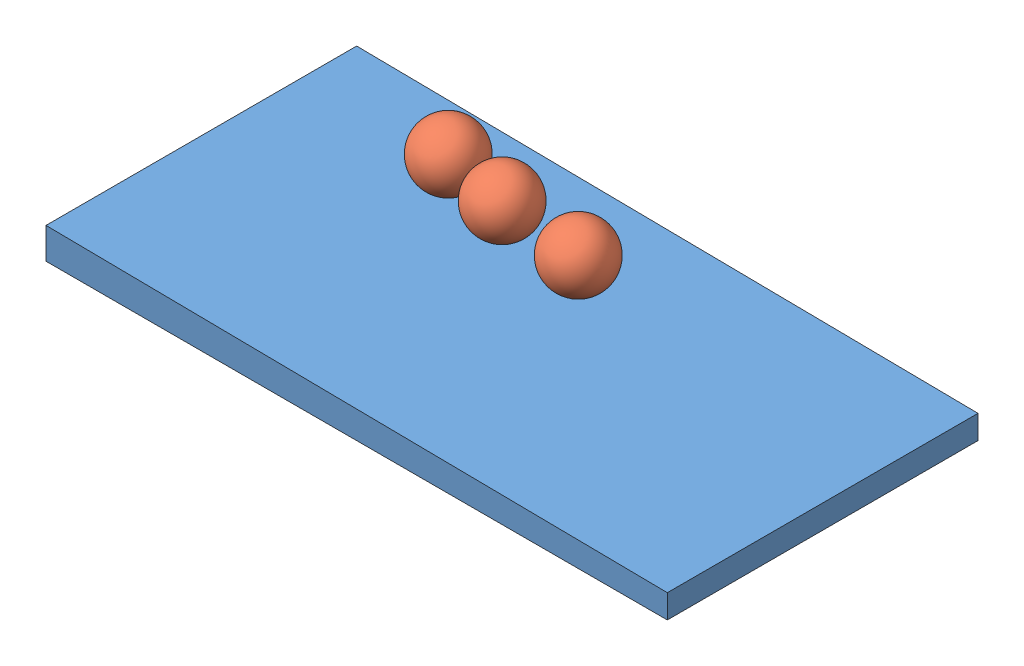
SolidWorks assembly Assem1, configuration ﾃﾞﾌｫﾙﾄ. Lengths in mm.
Overall size (200 34.42 100).
4 component instances, 2 part files, 3 mates.
Components (placement in the parent):
- 板-1: 板 [ﾃﾞﾌｫﾙﾄ] at (-14.4719 5.2827 200) size (200 10 100)
- Copy of 直径２０mmのパチンコ玉^Assem1-1: Copy of 直径２０mmのパチンコ玉^Assem1 [ﾃﾞﾌｫﾙﾄ] at (-11.6871 24.056 181.454) x (-0.958709 0.280638 -0.046044) z (0.07397 0.402403 0.912469) size (20 20 20) (virtual)
- Copy of 直径２０mmのパチンコ玉^Assem1-2: Copy of 直径２０mmのパチンコ玉^Assem1 [ﾃﾞﾌｫﾙﾄ] at (-60.215 24.6355 174.7735) x (-0.53463 -0.715781 0.449252) z (0.558454 0.099751 0.823516) size (20 20 20) (virtual)
- Copy of 直径２０mmのパチンコ玉^Assem1-3: Copy of 直径２０mmのパチンコ玉^Assem1 [ﾃﾞﾌｫﾙﾄ] at (-38.8183 24.38 178.8186) x (-0.863576 -0.070244 -0.499302) z (-0.344174 -0.641556 0.685529) size (20 20 20) (virtual)
Mates (geometry in assembly coordinates):
- 正接1: tangent anti-aligned: plane of 板-1 through (85.5281 12.8945 150) normal (0.01194 0.999929 0); sphere of Copy of 直径２０mmのパチンコ玉^Assem1-2
- 正接2: tangent anti-aligned: plane of 板-1 through (85.5281 12.8945 150) normal (0.01194 0.999929 0); sphere of Copy of 直径２０mmのパチンコ玉^Assem1-1
- 正接3: tangent anti-aligned: plane of 板-1 through (85.5281 12.8945 150) normal (0.01194 0.999929 0); sphere of Copy of 直径２０mmのパチンコ玉^Assem1-3
